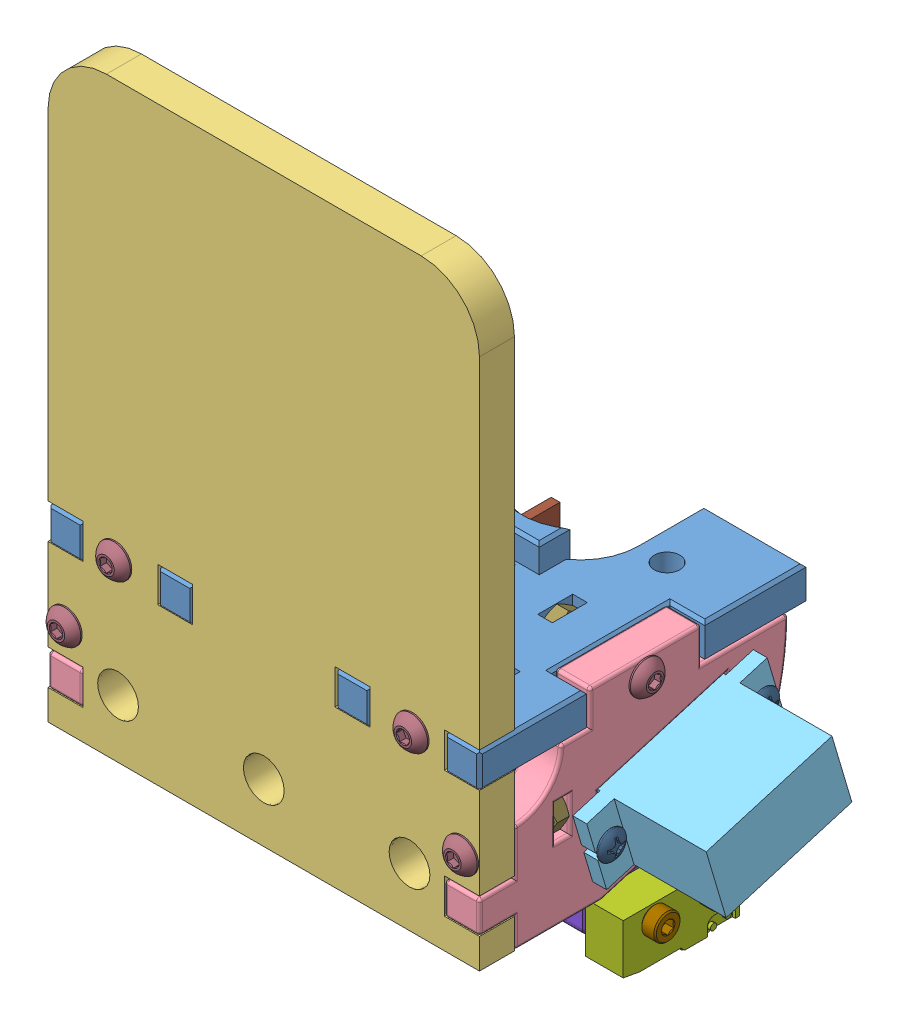
SolidWorks assembly XCarriageShelfAssembly, configuration Default. Lengths in mm.
33 component instances, 15 part files, 66 mates.
Components (placement in the parent):
- XCarriageDoubleShelf-1: XCarriageDoubleShelf [Default] at (-37 0 -50) x (1 0 0) z (0 0 -1) size (74 10.95 56)
- 25x25x10Fan-1: 25x25x10Fan [Default] at (-0.033 8 -12.717) x (1 0 0) z (0 -1 0) size (25 25 10)
- XCarriageBackPlate-1: XCarriageBackPlate [Default] at (-37 -32.5 0) size (74 101.26 6)
- ServoShelfBracket-1: ServoShelfBracket [Hot End Wiring Vent] at (-31 -6 0) x (0 0 -1) z (1 0 0) size (53 32.5 6)
- ServoShelfBracket-2: ServoShelfBracket [HXT900] at (37 -6 0) x (0 0 -1) z (1 0 0) size (53 32.5 6)
- Servo-HXT900-1: Servo-HXT900 [Default] at (55.2 -23.6377 -24.0991) x (0 -0.284598 0.958647) z (-1 0 0) size (32.3 12 29.6)
- ZProbeAssembly-2: ZProbeAssembly [Default] at (38.1869 -15.2356 -18.2927) x (0 -1 0.000275) z (0 -0.000275 -1) size (39.46 14.76 19.99)
  - Servo Horn-1: Servo Horn [Default] at (34.2536 11.8969 23.9402) size (19.66 4.12 7.35)
  - SnapLimitSwitch-1: SnapLimitSwitch [Default] at (22.9628 5.2957 11.2222) x (0.000181 0 -1) z (0 -1 0) size (19.99 14.86 6.5)
  - ZProbeArmMirrored-1: ZProbeArmMirrored [Default] at (-0.0025 17.1137 27.8606) x (1 0 0.000181) z (0.000181 0 -1) size (33.66 4.95 19.95)
  - M2.5x10HexSocketScrew-1: M2.5x10HexSocketScrew [91292A014] at (25.3259 12.0445 6.4347) x (-0.001575 0 0.999999) z (0 1 0) size (4.5 4.5 13.01)
  - M2.5x10HexSocketScrew-2: M2.5x10HexSocketScrew [91292A014] at (25.3241 12.0445 15.9347) x (-0.043466 0 0.999055) z (0 1 0) size (4.5 4.5 13.01)
  - ServoScrew-1: ServoScrew [93406A071] at (1.841 12.5869 13.9305) x (0.770997 0 -0.636839) z (0 1 0) size (4.93 5.18 10.49)
- TightDoubleHexagonShroud-1: TightDoubleHexagonShroud [No Support] at (0 -6 0) x (1 0 0) z (0 0 -1) size (57.71 23.73 44.86)
- M3HexNut-1: M3HexNut [90591A121] at (25.5 -3 -8.2) x (0.5 -0.866025 0) z (-0.866025 -0.5 0) size (5.5 2.58 6.35)
- M3HexNut-2: M3HexNut [90591A121] at (-25.5 -3 -8.2) x (0.5 0.866025 0) z (0.866025 -0.5 0) size (5.5 2.58 6.35)
- M3HexNut-3: M3HexNut [90591A121] at (22.8 -3 -22.5) x (0 0.866025 -0.5) z (0 -0.5 -0.866025) size (5.5 2.58 6.35)
- M3HexNut-4: M3HexNut [90591A121] at (34 -17 -8.2) x (0 -1 0) z (-1 0 0) size (5.5 2.58 6.35)
- M3HexNut-5: M3HexNut [90591A121] at (-22.8 -3 -22.5) x (0 0 1) z (0 -1 0) size (5.5 2.58 6.35)
- M3HexNut-6: M3HexNut [90591A121] at (-34 -17 -8.2) x (0.866025 -0.5 0) z (-0.5 -0.866025 0) size (5.5 2.58 6.35)
- M3x16HexButtonScrew-1: M3x16HexButtonScrew [92095A184] at (-34 -16.66 7.65) x (-0.998703 -0.050923 0) z (0 0 1) size (5.7 5.7 18)
- M3x16HexButtonScrew-2: M3x16HexButtonScrew [92095A184] at (34 -16.66 7.65) x (-0.989904 -0.141742 0) z (0 0 1) size (5.7 5.7 18)
- M3x16HexButtonScrew-3: M3x16HexButtonScrew [92095A184] at (-38.65 -3 -22.5) x (0 0 1) z (-1 0 0) size (5.7 5.7 18)
- M3x16HexButtonScrew-4: M3x16HexButtonScrew [92095A184] at (-25.5 -2.66 7.65) x (-0.998612 -0.052676 0) z (0 0 1) size (5.7 5.7 18)
- M3x16HexButtonScrew-5: M3x16HexButtonScrew [92095A184] at (25.5 -2.66 7.65) x (-0.862505 0.506048 0) z (0 0 1) size (5.7 5.7 18)
- M3x16HexButtonScrew-6: M3x16HexButtonScrew [92095A184] at (38.65 -3 -22.5) x (0 0 -1) z (1 0 0) size (5.7 5.7 18)
- ServoScrew-1: ServoScrew [93406A071] at (39.4 -22.4735 -14.0563) x (0 0 -1) z (1 0 0) size (4.93 5.18 10.49)
- ServoScrew-2: ServoScrew [93406A071] at (39.4 -14.6755 -40.3232) x (0 0 -1) z (1 0 0) size (4.93 5.18 10.49)
- M3x6HexButtonScrew-1: M3x6HexButtonScrew [92095A179] at (-20 -8.85 -15) x (0.893992 0 0.448083) z (0 -1 0) size (5.7 5.7 7.94)
- M3x6HexButtonScrew-2: M3x6HexButtonScrew [92095A179] at (20 -8.85 -15) x (0.837169 0 0.546944) z (0 -1 0) size (5.7 5.7 7.94)
- M3x12HexFlatScrew-1: M3x12HexFlatScrew [92125A132] at (-10.033 -6 -2.717) x (0.837169 0 0.546944) z (0 -1 0) size (6 6 12.31)
- M3x12HexFlatScrew-2: M3x12HexFlatScrew [92125A132] at (9.967 -6 -22.717) x (0.837169 0 0.546944) z (0 -1 0) size (6 6 12.31)
- M3x12HexFlatScrew-3: M3x12HexFlatScrew [92125A132] at (9.967 -6 -2.717) x (0.837169 0 0.546944) z (0 -1 0) size (6 6 12.31)
Mates (geometry in assembly coordinates):
- Coincident51: coincident anti-aligned: plane of XCarriageDoubleShelf-1 through (10.75 -2 -23.5) normal (0 1 0); plane of 25x25x10Fan-1 through (-0.033 -2 -12.717) normal (0 -1 0)
- Concentric25: concentric anti-aligned: cylinder of XCarriageDoubleShelf-1 through (-10.033 -6 -2.717) axis (0 -1 0) radius 1.8; cylinder of 25x25x10Fan-1 through (-10.033 -2 -2.717) axis (0 1 0) radius 1.397
- Parallel6: parallel anti-aligned: line of XCarriageDoubleShelf-1 through (-10.75 -2 0) axis (1 0 0); line of 25x25x10Fan-1 through (9.967 -2 -0.217) axis (-1 0 0)
- Coincident54: coincident aligned: plane of XCarriageDoubleShelf-1 through (-37 0 -50) normal (0 1 0); plane of ServoShelfBracket-2 through (37 0 0) normal (0 1 0)
- Coincident55: coincident aligned: plane of XCarriageDoubleShelf-1 through (37 -6 -50) normal (1 0 0); plane of ServoShelfBracket-2 through (37 -6 0) normal (1 0 0)
- Coincident56: coincident aligned: plane of XCarriageDoubleShelf-1 through (-37 0 -50) normal (0 1 0); plane of ServoShelfBracket-1 through (-31 0 0) normal (0 1 0)
- Coincident57: coincident aligned: plane of XCarriageDoubleShelf-1 through (-37 -6 -50) normal (-1 0 0); plane of ServoShelfBracket-1 through (-37 -6 0) normal (-1 0 0)
- Coincident59: coincident aligned: plane of XCarriageDoubleShelf-1 through (-37 0 6) normal (0 0 1); plane of XCarriageBackPlate-1 through (-37 -32.5 6) normal (0 0 1)
- Coincident35: coincident aligned: plane of XCarriageBackPlate-1 through (-37 -32.5 6) normal (-1 0 0); plane of ServoShelfBracket-1 through (-37 -6 0) normal (-1 0 0)
- Coincident37: coincident aligned: plane of XCarriageBackPlate-1 through (-37 -32.5 6) normal (0 0 1); plane of ServoShelfBracket-1 through (-31 -6 6) normal (0 0 1)
- Coincident58: coincident aligned: plane of ServoShelfBracket-2 through (37 -6 6) normal (0 0 1); plane of XCarriageBackPlate-1 through (-37 -32.5 6) normal (0 0 1)
- Concentric13: concentric anti-aligned: cylinder of ServoShelfBracket-2 through (30.999 -14.6755 -40.3232) axis (1 0 0) radius 0.75; cylinder of Servo-HXT900-1 through (55.201 -14.6755 -40.3232) axis (-1 0 0) radius 1
- Concentric14: concentric anti-aligned: cylinder of ServoShelfBracket-2 through (30.999 -22.4735 -14.0563) axis (1 0 0) radius 0.75; cylinder of Servo-HXT900-1 through (55.201 -22.4735 -14.0563) axis (-1 0 0) radius 1
- Coincident30: coincident anti-aligned: plane of ServoShelfBracket-2 through (37 -6 0) normal (1 0 0); plane of Servo-HXT900-1 through (37 -8.2264 -40.9643) normal (-1 0 0)
- Coincident60: coincident aligned: plane of XCarriageBackPlate-1 through (-37 -32.5 6) normal (0 -1 0); plane of ServoShelfBracket-1 through (-37 -32.5 0) normal (0 -1 0)
- Symmetric1: symmetric aligned: plane of XCarriageBackPlate-1 through (-37 -32.5 6) normal (-1 0 0); plane of XCarriageBackPlate-1 through (37 -32.5 6) normal (1 0 0); plane of assembly through (0 0 0) normal (1 0 0)
- Coincident62: coincident aligned: plane of XCarriageDoubleShelf-1 through (-37 0 -50) normal (0 1 0); plane of assembly through (0 0 0) normal (0 1 0)
- Coincident64: coincident anti-aligned: plane of XCarriageBackPlate-1 through (-37 -32.5 0) normal (0 0 -1); plane of assembly through (0 0 0) normal (0 0 1)
- Coincident65: coincident aligned: circle of Servo-HXT900-1; circle of ZProbeAssembly-2/Servo Horn-1
- Coincident69: coincident anti-aligned: plane of XCarriageBackPlate-1 through (-37 -32.5 0) normal (0 0 -1); plane of TightDoubleHexagonShroud-1 through (3.1415 -28.6306 0) normal (0 0 1)
- Coincident70: coincident anti-aligned: plane of XCarriageDoubleShelf-1 through (-37 -6 -50) normal (0 -1 0); plane of TightDoubleHexagonShroud-1 through (0 -6 0) normal (0 1 0)
- Coincident71: coincident aligned: plane of TightDoubleHexagonShroud-1; plane of assembly through (0 0 0) normal (1 0 0)
- Concentric28: concentric anti-aligned: cylinder of XCarriageDoubleShelf-1 through (19 -3 -22.5) axis (1 0 0) radius 1.7; circle of M3HexNut-3
- Parallel8: parallel aligned: plane of XCarriageDoubleShelf-1 through (21.5 0.001 -19.5) normal (0 0 -1); plane of M3HexNut-3 through (24 -4.5877 -25.25) normal (0 0 -1)
- Coincident75: coincident anti-aligned: plane of XCarriageDoubleShelf-1 through (24 0.001 -25.5) normal (-1 0 0); plane of M3HexNut-3 through (24 0.1754 -22.5) normal (1 0 0)
- Concentric29: concentric anti-aligned: cylinder of XCarriageDoubleShelf-1 through (25.5 -3 -12) axis (0 0 1) radius 1.7; circle of M3HexNut-1
- Parallel9: parallel aligned: plane of XCarriageDoubleShelf-1 through (22.5 0.001 -9.5) normal (1 0 0); plane of M3HexNut-1 through (28.25 -4.5877 -7) normal (1 0 0)
- Coincident77: coincident anti-aligned: plane of XCarriageDoubleShelf-1 through (22.5 0.001 -7) normal (0 0 -1); plane of M3HexNut-1 through (28.25 -4.5877 -7) normal (0 0 1)
- Concentric30: concentric anti-aligned: cylinder of XCarriageDoubleShelf-1 through (-25.5 -3 -12) axis (0 0 1) radius 1.7; circle of M3HexNut-2
- Parallel10: parallel aligned: plane of XCarriageDoubleShelf-1 through (-22.5 0.001 -9.5) normal (-1 0 0); plane of M3HexNut-2 through (-28.25 -1.4123 -7) normal (-1 0 0)
- Coincident79: coincident anti-aligned: plane of XCarriageDoubleShelf-1 through (-28.5 0.001 -7) normal (0 0 -1); plane of M3HexNut-2 through (-25.5 0.1754 -7) normal (0 0 1)
- Concentric31: concentric anti-aligned: cylinder of XCarriageDoubleShelf-1 through (-19 -3 -22.5) axis (-1 0 0) radius 1.7; circle of M3HexNut-5
- Concentric32: concentric anti-aligned: cylinder of ServoShelfBracket-1 through (-34 -17 -12) axis (0 0 1) radius 1.7; circle of M3HexNut-6
- Parallel11: parallel aligned: plane of ServoShelfBracket-1 through (-37.001 -20 -7) normal (0 1 0); plane of M3HexNut-6 through (-32.4123 -14.25 -7) normal (0 1 0)
- Coincident81: coincident anti-aligned: plane of ServoShelfBracket-1 through (-37.001 -14 -7) normal (0 0 -1); plane of M3HexNut-6 through (-30.8246 -17 -7) normal (0 0 1)
- Concentric33: concentric anti-aligned: cylinder of ServoShelfBracket-2 through (34 -17 -12) axis (0 0 1) radius 1.7; circle of M3HexNut-4
- Parallel12: parallel anti-aligned: plane of ServoShelfBracket-2 through (30.999 -20 -7) normal (0 1 0); plane of M3HexNut-4 through (32.4123 -19.75 -7) normal (0 -1 0)
- Coincident83: coincident anti-aligned: plane of ServoShelfBracket-2 through (30.999 -14 -7) normal (0 0 -1); plane of M3HexNut-4 through (35.5877 -19.75 -7) normal (0 0 1)
- Parallel13: parallel aligned: plane of XCarriageDoubleShelf-1 through (-24 0.001 -19.5) normal (0 0 -1); plane of M3HexNut-5 through (-24 -1.4123 -25.25) normal (0 0 -1)
- Coincident85: coincident anti-aligned: plane of XCarriageDoubleShelf-1 through (-24 0.001 -25.5) normal (1 0 0); plane of M3HexNut-5 through (-24 -1.4123 -19.75) normal (-1 0 0)
- Concentric34: concentric anti-aligned: cylinder of ServoShelfBracket-1 through (-37.001 -3 -22.5) axis (1 0 0) radius 1.7; circle of M3x16HexButtonScrew-3
- Coincident86: coincident anti-aligned: plane of ServoShelfBracket-1 through (-37 -6 0) normal (-1 0 0); plane of M3x16HexButtonScrew-3 through (-37 -5.85 -22.5) normal (1 0 0)
- Concentric35: concentric aligned: cylinder of XCarriageBackPlate-1 through (-25.5 -2.66 -0.001) axis (0 0 1) radius 1.5; circle of M3x16HexButtonScrew-4
- Coincident87: coincident anti-aligned: plane of XCarriageBackPlate-1 through (-37 -32.5 6) normal (0 0 1); plane of M3x16HexButtonScrew-4 through (-25.6501 0.186 6) normal (0 0 -1)
- Concentric36: concentric aligned: cylinder of XCarriageBackPlate-1 through (-34 -16.66 -0.001) axis (0 0 1) radius 1.5; circle of M3x16HexButtonScrew-1
- Coincident88: coincident anti-aligned: plane of XCarriageBackPlate-1 through (-37 -32.5 6) normal (0 0 1); plane of M3x16HexButtonScrew-1 through (-34.1451 -13.8137 6) normal (0 0 -1)
- Concentric37: concentric aligned: cylinder of XCarriageBackPlate-1 through (34 -16.66 -0.001) axis (0 0 1) radius 1.5; circle of M3x16HexButtonScrew-2
- Coincident90: coincident anti-aligned: plane of XCarriageBackPlate-1 through (-37 -32.5 6) normal (0 0 1); plane of M3x16HexButtonScrew-2 through (33.596 -13.8388 6) normal (0 0 -1)
- Concentric38: concentric aligned: cylinder of XCarriageBackPlate-1 through (25.5 -2.66 -0.001) axis (0 0 1) radius 1.5; circle of M3x16HexButtonScrew-5
- Coincident91: coincident anti-aligned: plane of XCarriageBackPlate-1 through (-37 -32.5 6) normal (0 0 1); plane of M3x16HexButtonScrew-5 through (26.9422 -0.2019 6) normal (0 0 -1)
- Concentric39: concentric aligned: cylinder of ServoShelfBracket-2 through (30.999 -3 -22.5) axis (1 0 0) radius 1.7; circle of M3x16HexButtonScrew-6
- Coincident92: coincident anti-aligned: plane of ServoShelfBracket-2 through (37 -6 0) normal (1 0 0); plane of M3x16HexButtonScrew-6 through (37 -5.85 -22.5) normal (-1 0 0)
- Concentric40: concentric aligned: circle of ServoScrew-1; cylinder of Servo-HXT900-1 through (55.201 -22.4735 -14.0563) axis (-1 0 0) radius 1
- Coincident93: coincident anti-aligned: plane of Servo-HXT900-1 through (39.4 -8.2264 -40.9643) normal (1 0 0); plane of ServoScrew-1 through (39.4 -22.4735 -14.0563) normal (-1 0 0)
- Concentric41: concentric aligned: cylinder of Servo-HXT900-1 through (55.201 -14.6755 -40.3232) axis (-1 0 0) radius 1; circle of ServoScrew-2
- Coincident94: coincident anti-aligned: plane of Servo-HXT900-1 through (39.4 -8.2264 -40.9643) normal (1 0 0); plane of ServoScrew-2 through (39.4 -14.6755 -40.3232) normal (-1 0 0)
- Concentric44: concentric anti-aligned: cylinder of XCarriageDoubleShelf-1 through (20 -6 -15) axis (0 1 0) radius 1.2; circle of M3x6HexButtonScrew-2
- Coincident97: coincident anti-aligned: plane of TightDoubleHexagonShroud-1 through (22.4353 -7.2 -10.2962) normal (0 -1 0); plane of M3x6HexButtonScrew-2 through (21.5588 -7.2 -17.3859) normal (0 1 0)
- Concentric45: concentric anti-aligned: cylinder of XCarriageDoubleShelf-1 through (-20 -6 -15) axis (0 1 0) radius 1.2; circle of M3x6HexButtonScrew-1
- Coincident98: coincident anti-aligned: plane of TightDoubleHexagonShroud-1 through (22.4353 -7.2 -10.2962) normal (0 -1 0); plane of M3x6HexButtonScrew-1 through (-18.723 -7.2 -17.5479) normal (0 1 0)
- Concentric46: concentric anti-aligned: cylinder of 25x25x10Fan-1 through (9.967 -2 -2.717) axis (0 1 0) radius 1.397; circle of M3x12HexFlatScrew-3
- Concentric47: concentric anti-aligned: cylinder of 25x25x10Fan-1 through (-10.033 -2 -2.717) axis (0 1 0) radius 1.397; circle of M3x12HexFlatScrew-1
- Concentric48: concentric anti-aligned: cylinder of 25x25x10Fan-1 through (9.967 -2 -22.717) axis (0 1 0) radius 1.397; circle of M3x12HexFlatScrew-2
- Coincident99: coincident aligned: plane of XCarriageDoubleShelf-1 through (-37 -6 -50) normal (0 -1 0); plane of M3x12HexFlatScrew-3 through (10.7874 -6 -3.9728) normal (0 -1 0)
- Coincident100: coincident aligned: plane of XCarriageDoubleShelf-1 through (-37 -6 -50) normal (0 -1 0); plane of M3x12HexFlatScrew-2 through (10.7874 -6 -23.9728) normal (0 -1 0)
- Coincident101: coincident aligned: plane of XCarriageDoubleShelf-1 through (-37 -6 -50) normal (0 -1 0); plane of M3x12HexFlatScrew-1 through (-9.2126 -6 -3.9728) normal (0 -1 0)
